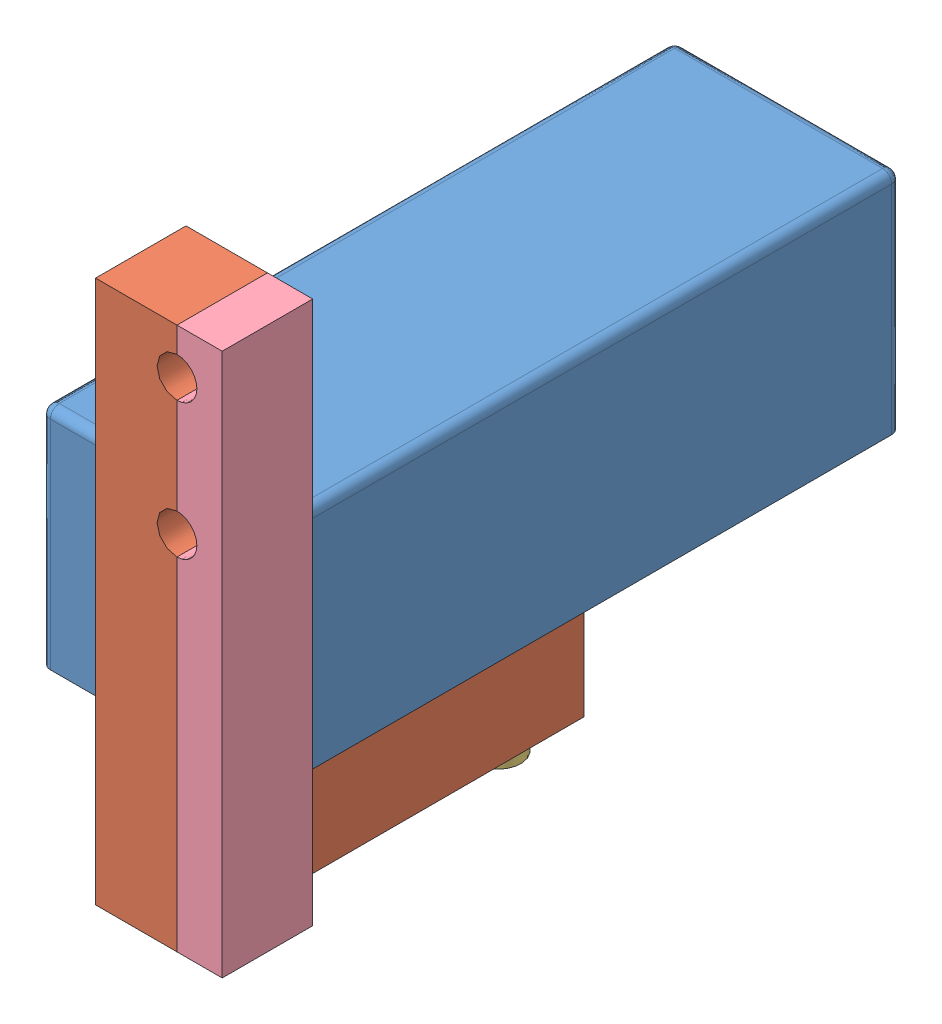
SolidWorks assembly bremse rechts, configuration Standard. Lengths in mm.
Overall size (30 63 80).
5 component instances, 4 part files, 9 mates.
Components (placement in the parent):
- bremsklotz-rechts-1: bremsklotz-rechts [Standard] at (19.8341 -14.4106 0) size (25 25 70)
- winkel-1: winkel [Standard] at (-0.2843 -21.9001 44.8997) x (1 0 0) z (0 -1 0) size (9 45 60)
- 10_M3_imbus-1: 10_M3_imbus [Standard] at (0.1247 -11.9001 40.077) x (-0.837169 0 -0.546944) z (-0.546944 0 0.837169) size (5 13 5)
- 10_M3_imbus-2: 10_M3_imbus [Standard] at (0.1247 -11.9001 65.077) x (-0.837169 0 -0.546944) z (-0.546944 0 0.837169) size (5 13 5)
- winkelzusatz-1: winkelzusatz [Standard] at (15.8846 38.0999 74.3153) x (1 0 0) z (0 -1 0) size (5 10 60)
Mates (geometry in assembly coordinates):
- Deckungsgleich1: coincident anti-aligned: plane of bremsklotz-rechts-1 through (-12.0847 -11.9001 70) normal (0 -1 0); plane of winkel-1 through (3.9153 -11.9001 35) normal (0 1 0)
- Deckungsgleich2: coincident aligned: axis of bremsklotz-rechts-1; axis of winkel-1
- Deckungsgleich3: coincident aligned: axis of bremsklotz-rechts-1; axis of winkel-1
- Konzentrisch1: concentric aligned: circle of winkel-1 centre (8.4153 -21.9001 65) axis (0 -1 0); circle of 10_M3_imbus-2 centre (8.4153 -21.9001 65) axis (0 -1 0)
- Konzentrisch2: concentric aligned: circle of winkel-1 centre (8.4153 -21.9001 40) axis (0 -1 0); circle of 10_M3_imbus-1 centre (8.4153 -21.9001 40) axis (0 -1 0)
- Deckungsgleich4: coincident anti-aligned: plane of winkel-1 through (3.9153 -21.9001 35) normal (0 -1 0); plane of 10_M3_imbus-2 through (8.4153 -21.9001 65) normal (0 1 0)
- Deckungsgleich5: coincident anti-aligned: plane of winkel-1 through (3.9153 -21.9001 35) normal (0 -1 0); plane of 10_M3_imbus-1 through (8.4153 -21.9001 40) normal (0 1 0)
- Deckungsgleich6: coincident anti-aligned: line of winkel-1; line of winkelzusatz-1
- Deckungsgleich7: coincident anti-aligned: unknown of winkel-1; unknown of winkelzusatz-1
